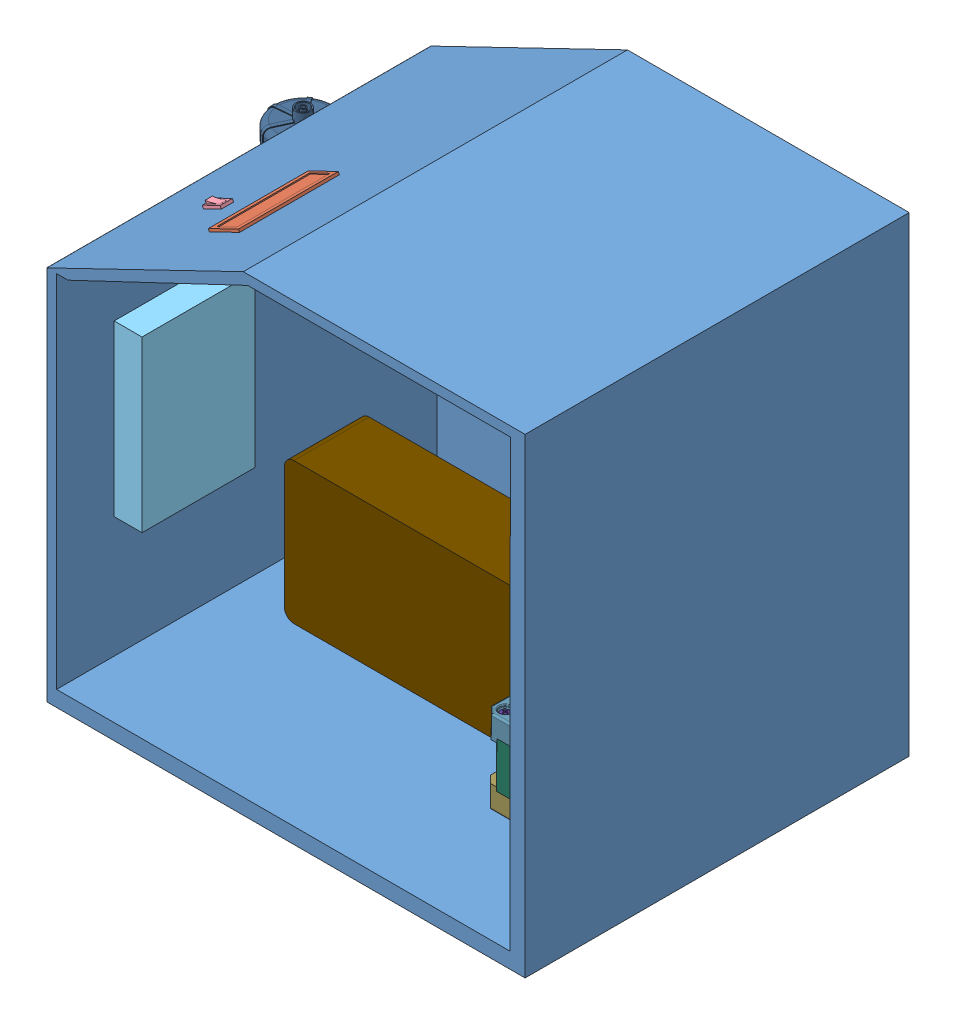
SolidWorks assembly proj, configuration Default. Lengths in mm.
Overall size (578.73 500 408).
111 component instances, 21 part files, 25 mates.
Components (placement in the parent):
- Part1-1: Part1 [Default] at (236.394 125.0948 463.982) size (510.74 500 408)
- lcd-1: lcd [Default] at (124.7878 588.2311 607.0046) x (0 0 -1) z (-0.435067 0.900398 0) size (122 44 15.99)
  - JUMBO LCD-1: JUMBO LCD [Default] at origin size (122 44 7.1)
  - zl201-16_p2-54_l40-6_w2-54_h8-9-1: zl201-16_p2-54_l40-6_w2-54_h8-9 [Default] at (10.98 2.5 0) x (1 0 0) z (0 1 0) size (40.64 11.94 2.54)
- button-1: button [Default] at (47.3144 555.665 552.0056) x (0 0 1) z (-0.900398 -0.435067 0) size (13 11 21)
- blood stepper-1: blood stepper [Default] at (-17.7234 360.4502 547.5779) x (0 0 1) z (0 -1 0) size (124 70 184)
- electro-1: electro [Default] at (431.8834 395.7604 136.8264) size (44.91 58 36)
  - ele01-1: ele01 [Default] at (14.0459 -19.7088 127.9371) x (0 0 -1) z (-1 0 0) size (25 30 43)
  - ele-1: ele [Default] at (14.0459 -47.7088 152.9371) x (-1 0 0) z (0 0 -1) size (26 27 34)
  - ele1-1: ele1 [Default] at (0.8753 -19.7088 141.2701) x (-0.999765 0 -0.021658) z (0 1 0) size (34.5 23 28)
  - pan head cross recess screw_iso-6: pan head cross recess screw_iso [ISO 7045 - M3 x 6 - Z - 6S] at (9.1738 -12.3088 133.3235) x (0 -1 0) z (0 0 1) size (8.35 5.6 5.6)
  - pan head cross recess screw_iso-7: pan head cross recess screw_iso [ISO 7045 - M3 x 6 - Z - 6S] at (9.1666 -12.3088 149.576) x (0 -1 0) z (0.198175 0 0.980167) size (8.35 5.6 5.6)
  - pan head cross recess screw_iso-8: pan head cross recess screw_iso [ISO 7045 - M3 x 6 - Z - 6S] at (-7.0859 -12.3088 149.5689) x (0 -1 0) z (0 0 1) size (8.35 5.6 5.6)
  - pan head cross recess screw_iso-9: pan head cross recess screw_iso [ISO 7045 - M3 x 6 - Z - 6S] at (-7.0787 -12.3088 133.3164) x (0 -1 0) z (0 0 1) size (8.35 5.6 5.6)
- 1.8 with cap.-1: 1.8 with cap. [Default] at (39.4621 228.7969 560.5041) x (-0.996152 0 0.087643) z (-0.087643 0 -0.996152) size (66.4 294.5 92.66)
- electro-2: electro [Default] at (369.7562 395.5489 136.8264) size (44.91 58 36)
  - ele01-1: ele01 [Default] at (14.0459 -19.7088 127.9371) x (0 0 -1) z (-1 0 0) size (25 30 43)
  - ele-1: ele [Default] at (14.0459 -47.7088 152.9371) x (-1 0 0) z (0 0 -1) size (26 27 34)
  - ele1-1: ele1 [Default] at (0.8753 -19.7088 141.2701) x (-0.999765 0 -0.021658) z (0 1 0) size (34.5 23 28)
  - pan head cross recess screw_iso-6: pan head cross recess screw_iso [ISO 7045 - M3 x 6 - Z - 6S] at (9.1738 -12.3088 133.3235) x (0 -1 0) z (0 0 1) size (8.35 5.6 5.6)
  - pan head cross recess screw_iso-7: pan head cross recess screw_iso [ISO 7045 - M3 x 6 - Z - 6S] at (9.1666 -12.3088 149.576) x (0 -1 0) z (0.198175 0 0.980167) size (8.35 5.6 5.6)
  - pan head cross recess screw_iso-8: pan head cross recess screw_iso [ISO 7045 - M3 x 6 - Z - 6S] at (-7.0859 -12.3088 149.5689) x (0 -1 0) z (0 0 1) size (8.35 5.6 5.6)
  - pan head cross recess screw_iso-9: pan head cross recess screw_iso [ISO 7045 - M3 x 6 - Z - 6S] at (-7.0787 -12.3088 133.3164) x (0 -1 0) z (0 0 1) size (8.35 5.6 5.6)
- electro-3: electro [Default] at (311.3751 395.6908 136.8264) size (44.91 58 36)
  - ele01-1: ele01 [Default] at (14.0459 -19.7088 127.9371) x (0 0 -1) z (-1 0 0) size (25 30 43)
  - ele-1: ele [Default] at (14.0459 -47.7088 152.9371) x (-1 0 0) z (0 0 -1) size (26 27 34)
  - ele1-1: ele1 [Default] at (0.8753 -19.7088 141.2701) x (-0.999765 0 -0.021658) z (0 1 0) size (34.5 23 28)
  - pan head cross recess screw_iso-6: pan head cross recess screw_iso [ISO 7045 - M3 x 6 - Z - 6S] at (9.1738 -12.3088 133.3235) x (0 -1 0) z (0 0 1) size (8.35 5.6 5.6)
  - pan head cross recess screw_iso-7: pan head cross recess screw_iso [ISO 7045 - M3 x 6 - Z - 6S] at (9.1666 -12.3088 149.576) x (0 -1 0) z (0.198175 0 0.980167) size (8.35 5.6 5.6)
  - pan head cross recess screw_iso-8: pan head cross recess screw_iso [ISO 7045 - M3 x 6 - Z - 6S] at (-7.0859 -12.3088 149.5689) x (0 -1 0) z (0 0 1) size (8.35 5.6 5.6)
  - pan head cross recess screw_iso-9: pan head cross recess screw_iso [ISO 7045 - M3 x 6 - Z - 6S] at (-7.0787 -12.3088 133.3164) x (0 -1 0) z (0 0 1) size (8.35 5.6 5.6)
- electro-4: electro [Default] at (250.9701 395.7415 136.8264) size (44.91 58 36)
  - ele01-1: ele01 [Default] at (14.0459 -19.7088 127.9371) x (0 0 -1) z (-1 0 0) size (25 30 43)
  - ele-1: ele [Default] at (14.0459 -47.7088 152.9371) x (-1 0 0) z (0 0 -1) size (26 27 34)
  - ele1-1: ele1 [Default] at (0.8753 -19.7088 141.2701) x (-0.999765 0 -0.021658) z (0 1 0) size (34.5 23 28)
  - pan head cross recess screw_iso-6: pan head cross recess screw_iso [ISO 7045 - M3 x 6 - Z - 6S] at (9.1738 -12.3088 133.3235) x (0 -1 0) z (0 0 1) size (8.35 5.6 5.6)
  - pan head cross recess screw_iso-7: pan head cross recess screw_iso [ISO 7045 - M3 x 6 - Z - 6S] at (9.1666 -12.3088 149.576) x (0 -1 0) z (0.198175 0 0.980167) size (8.35 5.6 5.6)
  - pan head cross recess screw_iso-8: pan head cross recess screw_iso [ISO 7045 - M3 x 6 - Z - 6S] at (-7.0859 -12.3088 149.5689) x (0 -1 0) z (0 0 1) size (8.35 5.6 5.6)
  - pan head cross recess screw_iso-9: pan head cross recess screw_iso [ISO 7045 - M3 x 6 - Z - 6S] at (-7.0787 -12.3088 133.3164) x (0 -1 0) z (0 0 1) size (8.35 5.6 5.6)
- electro-5: electro [Default] at (183.2334 394.1199 136.8264) size (44.91 58 36)
  - ele01-1: ele01 [Default] at (14.0459 -19.7088 127.9371) x (0 0 -1) z (-1 0 0) size (25 30 43)
  - ele-1: ele [Default] at (14.0459 -47.7088 152.9371) x (-1 0 0) z (0 0 -1) size (26 27 34)
  - ele1-1: ele1 [Default] at (0.8753 -19.7088 141.2701) x (-0.999765 0 -0.021658) z (0 1 0) size (34.5 23 28)
  - pan head cross recess screw_iso-6: pan head cross recess screw_iso [ISO 7045 - M3 x 6 - Z - 6S] at (9.1738 -12.3088 133.3235) x (0 -1 0) z (0 0 1) size (8.35 5.6 5.6)
  - pan head cross recess screw_iso-7: pan head cross recess screw_iso [ISO 7045 - M3 x 6 - Z - 6S] at (9.1666 -12.3088 149.576) x (0 -1 0) z (0.198175 0 0.980167) size (8.35 5.6 5.6)
  - pan head cross recess screw_iso-8: pan head cross recess screw_iso [ISO 7045 - M3 x 6 - Z - 6S] at (-7.0859 -12.3088 149.5689) x (0 -1 0) z (0 0 1) size (8.35 5.6 5.6)
  - pan head cross recess screw_iso-9: pan head cross recess screw_iso [ISO 7045 - M3 x 6 - Z - 6S] at (-7.0787 -12.3088 133.3164) x (0 -1 0) z (0 0 1) size (8.35 5.6 5.6)
- electro-6: electro [Default] at (120.2358 394.7528 136.8264) size (44.91 58 36)
  - ele01-1: ele01 [Default] at (14.0459 -19.7088 127.9371) x (0 0 -1) z (-1 0 0) size (25 30 43)
  - ele-1: ele [Default] at (14.0459 -47.7088 152.9371) x (-1 0 0) z (0 0 -1) size (26 27 34)
  - ele1-1: ele1 [Default] at (0.8753 -19.7088 141.2701) x (-0.999765 0 -0.021658) z (0 1 0) size (34.5 23 28)
  - pan head cross recess screw_iso-6: pan head cross recess screw_iso [ISO 7045 - M3 x 6 - Z - 6S] at (9.1738 -12.3088 133.3235) x (0 -1 0) z (0 0 1) size (8.35 5.6 5.6)
  - pan head cross recess screw_iso-7: pan head cross recess screw_iso [ISO 7045 - M3 x 6 - Z - 6S] at (9.1666 -12.3088 149.576) x (0 -1 0) z (0.198175 0 0.980167) size (8.35 5.6 5.6)
  - pan head cross recess screw_iso-8: pan head cross recess screw_iso [ISO 7045 - M3 x 6 - Z - 6S] at (-7.0859 -12.3088 149.5689) x (0 -1 0) z (0 0 1) size (8.35 5.6 5.6)
  - pan head cross recess screw_iso-9: pan head cross recess screw_iso [ISO 7045 - M3 x 6 - Z - 6S] at (-7.0787 -12.3088 133.3164) x (0 -1 0) z (0 0 1) size (8.35 5.6 5.6)
- electro-7: electro [Default] at (64.2225 392.6275 136.8264) size (44.91 58 36)
  - ele01-1: ele01 [Default] at (14.0459 -19.7088 127.9371) x (0 0 -1) z (-1 0 0) size (25 30 43)
  - ele-1: ele [Default] at (14.0459 -47.7088 152.9371) x (-1 0 0) z (0 0 -1) size (26 27 34)
  - ele1-1: ele1 [Default] at (0.8753 -19.7088 141.2701) x (-0.999765 0 -0.021658) z (0 1 0) size (34.5 23 28)
  - pan head cross recess screw_iso-6: pan head cross recess screw_iso [ISO 7045 - M3 x 6 - Z - 6S] at (9.1738 -12.3088 133.3235) x (0 -1 0) z (0 0 1) size (8.35 5.6 5.6)
  - pan head cross recess screw_iso-7: pan head cross recess screw_iso [ISO 7045 - M3 x 6 - Z - 6S] at (9.1666 -12.3088 149.576) x (0 -1 0) z (0.198175 0 0.980167) size (8.35 5.6 5.6)
  - pan head cross recess screw_iso-8: pan head cross recess screw_iso [ISO 7045 - M3 x 6 - Z - 6S] at (-7.0859 -12.3088 149.5689) x (0 -1 0) z (0 0 1) size (8.35 5.6 5.6)
  - pan head cross recess screw_iso-9: pan head cross recess screw_iso [ISO 7045 - M3 x 6 - Z - 6S] at (-7.0787 -12.3088 133.3164) x (0 -1 0) z (0 0 1) size (8.35 5.6 5.6)
- electro-8: electro [Default] at (438.3699 326.717 136.8264) size (44.91 58 36)
  - ele01-1: ele01 [Default] at (14.0459 -19.7088 127.9371) x (0 0 -1) z (-1 0 0) size (25 30 43)
  - ele-1: ele [Default] at (14.0459 -47.7088 152.9371) x (-1 0 0) z (0 0 -1) size (26 27 34)
  - ele1-1: ele1 [Default] at (0.8753 -19.7088 141.2701) x (-0.999765 0 -0.021658) z (0 1 0) size (34.5 23 28)
  - pan head cross recess screw_iso-6: pan head cross recess screw_iso [ISO 7045 - M3 x 6 - Z - 6S] at (9.1738 -12.3088 133.3235) x (0 -1 0) z (0 0 1) size (8.35 5.6 5.6)
  - pan head cross recess screw_iso-7: pan head cross recess screw_iso [ISO 7045 - M3 x 6 - Z - 6S] at (9.1666 -12.3088 149.576) x (0 -1 0) z (0.198175 0 0.980167) size (8.35 5.6 5.6)
  - pan head cross recess screw_iso-8: pan head cross recess screw_iso [ISO 7045 - M3 x 6 - Z - 6S] at (-7.0859 -12.3088 149.5689) x (0 -1 0) z (0 0 1) size (8.35 5.6 5.6)
  - pan head cross recess screw_iso-9: pan head cross recess screw_iso [ISO 7045 - M3 x 6 - Z - 6S] at (-7.0787 -12.3088 133.3164) x (0 -1 0) z (0 0 1) size (8.35 5.6 5.6)
- KDP-370EB12v-1: KDP-370EB12v [Default] at (423.2491 155.2685 349.5609) size (77.53 27.15 27.2)
- KDP-370EB12v-2: KDP-370EB12v [Default] at (422.1328 155.2685 433.8475) size (77.53 27.15 27.2)
- stepper-2: stepper [Default] at (401.5102 148.4227 521.6248) x (1 0 0) z (0 0.999919 -0.012725) size (84.6 84.6 136)
  - backPlate-1: backPlate [Default] at (30.6882 45.002 54.8281) size (84.6 84.6 28)
  - arbre axiale-1: arbre axiale [Default] at (30.6882 45.002 50.8281) x (-0.859783 -0.510659 0) z (0 0 1) size (10 10 136)
  - base-1: base [Default] at (72.9882 2.702 142.8281) x (-1 0 0) z (0 0 -1) size (84.6 84.6 24)
  - body-1: body [Default] at (30.6882 45.002 74.8281) size (84.6 84.6 48)
  - instrument ball bearing_68_am-4: instrument ball bearing_68_am [AFBMA 12.1.4.1 - 0090-24 - Full,DE,AC,Full_68] at (30.6882 45.002 139.3281) x (0 0 1) z (-0.918452 0.395532 0) size (7 24 24)
  - instrument ball bearing_68_am-5: instrument ball bearing_68_am [AFBMA 12.1.4.1 - 0090-24 - Full,DE,AC,Full_68] at (30.6882 45.002 61.3281) x (0 0 1) z (-0.976788 0.214208 0) size (7 24 24)
  - oval head_am-1: oval head_am [B18.6.7M - M5 x 0.8 x 13 Type I Cross Recessed OHMS --13S] at (61.6882 76.002 140.7742) x (0 0 -1) z (0.276926 0.960891 0) size (14.17 9.3 9.3)
  - oval head_am-2: oval head_am [B18.6.7M - M5 x 0.8 x 13 Type I Cross Recessed OHMS --13S] at (61.6882 14.002 140.7742) x (0 0 -1) z (0.994132 -0.108176 0) size (14.17 9.3 9.3)
  - oval head_am-3: oval head_am [B18.6.7M - M5 x 0.8 x 13 Type I Cross Recessed OHMS --13S] at (-0.3118 76.002 140.7742) x (0 0 -1) z (0.86317 -0.504913 0) size (14.17 9.3 9.3)
  - oval head_am-4: oval head_am [B18.6.7M - M5 x 0.8 x 13 Type I Cross Recessed OHMS --13S] at (-0.3118 14.002 140.7742) x (0 0 -1) z (1 0 0) size (14.17 9.3 9.3)
- stepper-3: stepper [Default] at (401.5102 151.0294 616.5749) x (1 0 0) z (0 0.999919 -0.012725) size (84.6 84.6 136)
  - backPlate-1: backPlate [Default] at (30.6882 45.002 54.8281) size (84.6 84.6 28)
  - arbre axiale-1: arbre axiale [Default] at (30.6882 45.002 50.8281) x (-0.859783 -0.510659 0) z (0 0 1) size (10 10 136)
  - base-1: base [Default] at (72.9882 2.702 142.8281) x (-1 0 0) z (0 0 -1) size (84.6 84.6 24)
  - body-1: body [Default] at (30.6882 45.002 74.8281) size (84.6 84.6 48)
  - instrument ball bearing_68_am-4: instrument ball bearing_68_am [AFBMA 12.1.4.1 - 0090-24 - Full,DE,AC,Full_68] at (30.6882 45.002 139.3281) x (0 0 1) z (-0.918452 0.395532 0) size (7 24 24)
  - instrument ball bearing_68_am-5: instrument ball bearing_68_am [AFBMA 12.1.4.1 - 0090-24 - Full,DE,AC,Full_68] at (30.6882 45.002 61.3281) x (0 0 1) z (-0.976788 0.214208 0) size (7 24 24)
  - oval head_am-1: oval head_am [B18.6.7M - M5 x 0.8 x 13 Type I Cross Recessed OHMS --13S] at (61.6882 76.002 140.7742) x (0 0 -1) z (0.276926 0.960891 0) size (14.17 9.3 9.3)
  - oval head_am-2: oval head_am [B18.6.7M - M5 x 0.8 x 13 Type I Cross Recessed OHMS --13S] at (61.6882 14.002 140.7742) x (0 0 -1) z (0.994132 -0.108176 0) size (14.17 9.3 9.3)
  - oval head_am-3: oval head_am [B18.6.7M - M5 x 0.8 x 13 Type I Cross Recessed OHMS --13S] at (-0.3118 76.002 140.7742) x (0 0 -1) z (0.86317 -0.504913 0) size (14.17 9.3 9.3)
  - oval head_am-4: oval head_am [B18.6.7M - M5 x 0.8 x 13 Type I Cross Recessed OHMS --13S] at (-0.3118 14.002 140.7742) x (0 0 -1) z (1 0 0) size (14.17 9.3 9.3)
- heatter-1: heatter [Default] at (188.2703 201.3662 402.277) x (1 0 0) z (0 -1 0) size (250 80 150)
- DST-1R8P-P optocoupler board assembly-1: DST-1R8P-P optocoupler board assembly [Default] at (474.4985 487.2718 404.6322) x (0 0 1) z (0 -1 0) size (95 17.1 72)
  - DST-1R8P-P optocoupler board-1: DST-1R8P-P optocoupler board [Default] at origin size (95 14.25 72)
  - 2 hole screw terminal-1: 2 hole screw terminal [Default] at (30.25 1.5 25.5) size (10.57 17.1 9)
  - 2 hole screw terminal-2: 2 hole screw terminal [Default] at (20.25 1.5 25.5) size (10.57 17.1 9)
  - 2 hole screw terminal-3: 2 hole screw terminal [Default] at (10.25 1.5 25.5) size (10.57 17.1 9)
  - 2 hole screw terminal-4: 2 hole screw terminal [Default] at (0.25 1.5 25.5) size (10.57 17.1 9)
  - 2 hole screw terminal-5: 2 hole screw terminal [Default] at (-9.75 1.5 25.5) size (10.57 17.1 9)
  - 2 hole screw terminal-6: 2 hole screw terminal [Default] at (-19.75 1.5 25.5) size (10.57 17.1 9)
  - 2 hole screw terminal-7: 2 hole screw terminal [Default] at (-29.75 1.5 25.5) size (10.57 17.1 9)
  - 2 hole screw terminal-8: 2 hole screw terminal [Default] at (-39.75 1.5 25.5) size (10.57 17.1 9)
  - 2 hole screw terminal-9: 2 hole screw terminal [Default] at (-5.1 1.5 -25.5) x (-1 0 0) z (0 0 -1) size (10.57 17.1 9)
  - 2 hole screw terminal-10: 2 hole screw terminal [Default] at (4.9 1.5 -25.5) x (-1 0 0) z (0 0 -1) size (10.57 17.1 9)
  - 2 hole screw terminal-11: 2 hole screw terminal [Default] at (14.9 1.5 -25.5) x (-1 0 0) z (0 0 -1) size (10.57 17.1 9)
  - 2 hole screw terminal-12: 2 hole screw terminal [Default] at (24.9 1.5 -25.5) x (-1 0 0) z (0 0 -1) size (10.57 17.1 9)
  - 2 hole screw terminal blue-1: 2 hole screw terminal blue [Default] at (-15.1 1.5 -25.5) x (-1 0 0) z (0 0 -1) size (10.57 17.1 9)
Mates (geometry in assembly coordinates):
- Coincident2: coincident anti-aligned: plane of Part1-1 through (95.7306 552.4046 599.0046) normal (0 0 -1); plane of lcd-1/JUMBO LCD-1 through (87.1962 570.0671 599.0046) normal (0 0 1)
- Coincident3: coincident anti-aligned: plane of Part1-1 through (95.7306 552.4046 493.0046) normal (0 0 1); plane of lcd-1/JUMBO LCD-1 through (119.1603 585.5119 493.0046) normal (0 0 -1)
- Coincident4: coincident anti-aligned: plane of Part1-1 through (95.7306 552.4046 493.0046) normal (0.900398 0.435067 0); plane of lcd-1/JUMBO LCD-1 through (87.1962 570.0671 493.0046) normal (-0.900398 -0.435067 0)
- Coincident5: coincident anti-aligned: plane of Part1-1 through (49.1143 529.8798 545.7374) normal (0 0 1); plane of button-1 through (49.4897 551.163 545.7374) normal (0 0 -1)
- Coincident6: coincident anti-aligned: plane of Part1-1 through (49.1143 529.8798 545.7374) normal (0.900398 0.435067 0); plane of button-1 through (40.848 546.9874 552.0056) normal (-0.900398 -0.435067 0)
- Coincident7: coincident anti-aligned: plane of Part1-1 through (31.9357 548.2341 234.7635) normal (-0.435067 0.900398 0); plane of button-1 through (47.3144 555.665 552.0056) normal (0.435067 -0.900398 0)
- Coincident10: coincident anti-aligned: line of Part1-1 through (-17.7234 450.048 488.6945) axis (0 0 1); line of blood stepper-1 through (-17.7234 450.048 607.5779) axis (0 0 -1)
- Coincident11: coincident aligned: line of Part1-1 through (-17.7234 270.048 608.6945) axis (0 0 -1); line of blood stepper-1 through (-17.7234 270.048 607.5779) axis (0 0 -1)
- Coincident12: coincident anti-aligned: plane of Part1-1 through (-17.7234 625.0948 260.7635) normal (-1 0 0); plane of blood stepper-1 through (-17.7234 360.4502 547.5779) normal (1 0 0)
- Coincident14: coincident anti-aligned: plane of Part1-1 through (236.394 125.0948 264.7635) normal (0 0 1); plane of electro-2/ele01-1 through (357.8021 373.8401 264.7635) normal (0 0 -1)
- Coincident15: coincident anti-aligned: plane of Part1-1 through (236.394 125.0948 264.7635) normal (0 0 1); plane of electro-1/ele01-1 through (419.9293 374.0516 264.7635) normal (0 0 -1)
- Coincident16: coincident anti-aligned: plane of Part1-1 through (236.394 125.0948 264.7635) normal (0 0 1); plane of electro-7/ele01-1 through (52.2684 370.9187 264.7635) normal (0 0 -1)
- Coincident17: coincident anti-aligned: plane of Part1-1 through (236.394 125.0948 264.7635) normal (0 0 1); plane of electro-8/ele01-1 through (426.4158 305.0082 264.7635) normal (0 0 -1)
- Coincident18: coincident anti-aligned: plane of Part1-1 through (236.394 125.0948 264.7635) normal (0 0 1); plane of electro-3/ele01-1 through (299.421 373.982 264.7635) normal (0 0 -1)
- Coincident19: coincident anti-aligned: plane of Part1-1 through (236.394 125.0948 264.7635) normal (0 0 1); plane of electro-4/ele01-1 through (239.016 374.0327 264.7635) normal (0 0 -1)
- Coincident20: coincident anti-aligned: plane of Part1-1 through (236.394 125.0948 264.7635) normal (0 0 1); plane of electro-5/ele01-1 through (171.2793 372.4111 264.7635) normal (0 0 -1)
- Coincident21: coincident anti-aligned: plane of Part1-1 through (236.394 125.0948 264.7635) normal (0 0 1); plane of electro-6/ele01-1 through (108.2817 373.044 264.7635) normal (0 0 -1)
- Tangent3: tangent anti-aligned: plane of Part1-1 through (-7.2891 141.7685 264.7635) normal (0 1 0); cylinder of KDP-370EB12v-1 through (361.0491 155.2685 349.5609) axis (1 0 0) radius 13.5
- Tangent4: tangent anti-aligned: plane of Part1-1 through (-7.2891 141.7685 264.7635) normal (0 1 0); cylinder of KDP-370EB12v-2 through (359.9328 155.2685 433.8475) axis (1 0 0) radius 13.5
- Coincident22: coincident anti-aligned: plane of Part1-1 through (474.4985 524.1788 264.7635) normal (-1 0 0); plane of stepper-2/body-1 through (474.4985 271.0283 503.3611) normal (1 0 0)
- Coincident23: coincident anti-aligned: plane of Part1-1 through (474.4985 524.1788 264.7635) normal (-1 0 0); plane of stepper-3/body-1 through (474.4985 273.6351 598.3112) normal (1 0 0)
- Tangent5: tangent anti-aligned: plane of Part1-1 through (-17.7234 625.0948 260.7635) normal (-1 0 0); cylinder of 1.8 with cap.-1 through (-50.1734 476.5973 364.1506) axis (0 1 0) radius 32.45
- Coincident24: coincident anti-aligned: plane of Part1-1 through (-7.2891 141.7685 264.7635) normal (0 1 0); plane of heatter-1 through (288.2703 141.7685 482.277) normal (0 -1 0)
- Coincident25: coincident anti-aligned: plane of Part1-1 through (474.4985 524.1788 264.7635) normal (-1 0 0); plane of DST-1R8P-P optocoupler board assembly-1/DST-1R8P-P optocoupler board-1 through (474.4985 487.2718 404.6322) normal (1 0 0)
- Coincident26: coincident anti-aligned: line of Part1-1 through (474.4985 523.2718 264.7635) axis (0 0 1); line of DST-1R8P-P optocoupler board assembly-1/DST-1R8P-P optocoupler board-1 through (474.4985 523.2718 452.1322) axis (0 0 -1)
